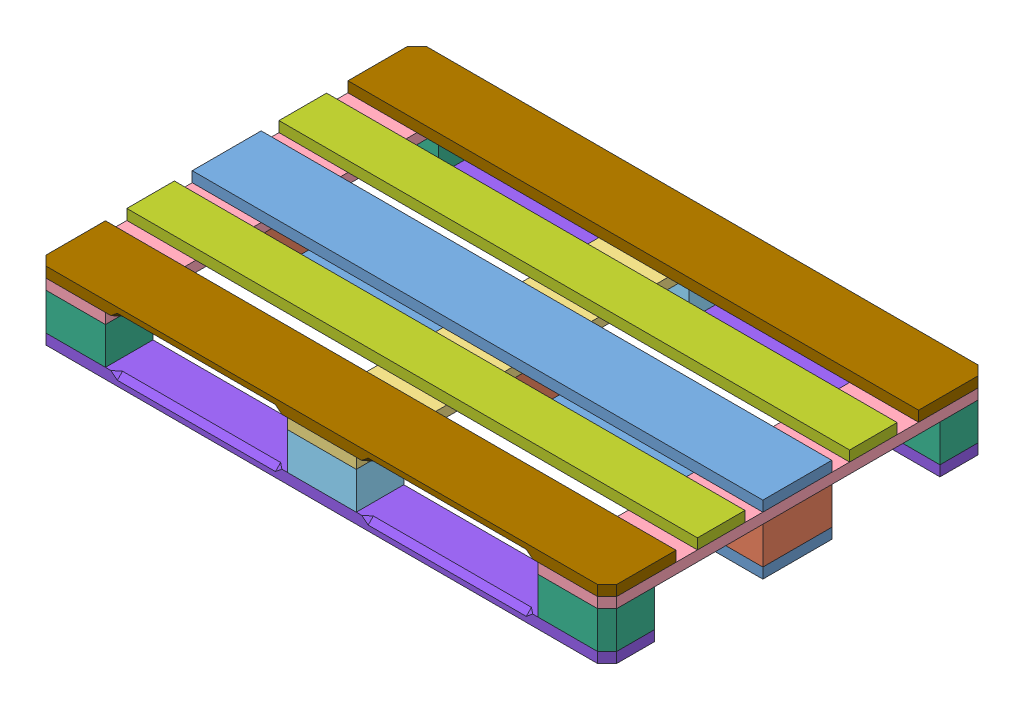
SolidWorks assembly PAL_EURO_120x80_EPAL, configuration Défaut. Lengths in mm.
Overall size (1200 144 800).
20 component instances, 9 part files, 62 mates.
Components (placement in the parent):
- brd-145x1200-1: brd-145x1200 [Default] x (-1 0 0) z (0 1 0) size (1200 145 22)
- blk-145x145-1: blk-145x145 [Default] at (0 22 0) x (-1 0 0) z (0 1 0) size (145 145 78)
- blk-145x145-2: blk-145x145 [Default] at (0 100 0) x (1 0 0) z (0 -1 0) size (145 145 78)
- blk-145x145-3: blk-145x145 [Default] at (0 100 527.5) x (0 0 -1) z (0 -1 0) size (145 145 78)
- brd-145x1200-2: brd-145x1200 [Default] at (0 144 0) x (1 0 0) z (0 -1 0) size (1200 145 22)
- trans-brd-cntr-145x800-1: trans-brd-cntr-145x800 [Default] at (0 122 0) x (0 0 1) z (0 -1 0) size (800 145 22)
- trans-brd-leader-145x800-1: trans-brd-leader-145x800 [Default] at (-600 122 0) x (0 0 1) z (0 -1 0) size (800 145 22)
- trans-brd-leader-145x800-2: trans-brd-leader-145x800 [Default] at (600 122 0) x (0 0 -1) z (0 -1 0) size (800 145 22)
- blk-100x145-1: blk-100x145 [Default] at (-527.5 22 -327.5) x (1 0 0) z (0 1 0) size (145 100 78)
- blk-100x145-2: blk-100x145 [Default] at (-527.5 100 327.5) x (1 0 0) z (0 -1 0) size (145 100 78)
- blk-100x145-corner-1: blk-100x145-corner [Default] at (455 22 -300) x (-1 0 0) z (0 1 0) size (145 100 78)
- blk-100x145-corner-2: blk-100x145-corner [Default] at (-455 22 300) x (1 0 0) z (0 1 0) size (145 100 78)
- blk-100x145-corner-3: blk-100x145-corner [Default] at (-455 100 -300) x (1 0 0) z (0 -1 0) size (145 100 78)
- blk-100x145-corner-4: blk-100x145-corner [Default] at (455 100 300) x (-1 0 0) z (0 -1 0) size (145 100 78)
- brd-100x1200-1: brd-100x1200 [Default] at (0 122 -160) x (1 0 0) z (0 1 0) size (1200 100 22)
- brd-100x1200-2: brd-100x1200 [Default] at (0 122 160) x (1 0 0) z (0 1 0) size (1200 100 22)
- leader deck brd bottom 100-1: leader deck brd bottom 100 [Défaut] at (0 0 350) x (0 0 -1) z (1 0 0) size (100 22 1200)
- leader deck brd bottom 100-2: leader deck brd bottom 100 [Défaut] at (0 0 -350) x (0 0 1) z (-1 0 0) size (100 22 1200)
- leader deck brd top 145-1: leader deck brd top 145 [Défaut] at (0 122 -327.5) x (0 0 1) z (-1 0 0) size (145 22 1200)
- leader deck brd top 145-2: leader deck brd top 145 [Défaut] at (0 122 327.5) x (0 0 -1) z (1 0 0) size (145 22 1200)
Mates (geometry in assembly coordinates):
- Coincident8: coincident: brd-145x1200-1, blk-145x145-1
- Coincident9: coincident: brd-145x1200-1, blk-145x145-1
- Coincident10: coincident: brd-145x1200-1, blk-145x145-1
- Coincident16: coincident: brd-145x1200-1, blk-145x145-2
- Coincident14: coincident: brd-145x1200-1, blk-145x145-2
- Coincident15: coincident: brd-145x1200-1, blk-145x145-2
- Coincident30: coincident: blk-145x145-1, trans-brd-leader-145x800-1
- Coincident31: coincident: blk-145x145-1, trans-brd-leader-145x800-1
- Coincident32: coincident: blk-145x145-1, trans-brd-leader-145x800-1
- Coincident33: coincident: blk-145x145-2, trans-brd-leader-145x800-2
- Coincident36: coincident: brd-145x1200-2, trans-brd-leader-145x800-2
- Coincident34: coincident: blk-145x145-2, trans-brd-leader-145x800-2
- Coincident35: coincident: blk-145x145-2, trans-brd-leader-145x800-2
- Coincident41: coincident: trans-brd-leader-145x800-2, blk-100x145-corner-4
- Coincident42: coincident: trans-brd-leader-145x800-2, blk-100x145-corner-4
- Coincident43: coincident: trans-brd-leader-145x800-2, blk-100x145-corner-4
- Coincident44: coincident: trans-brd-leader-145x800-1, blk-100x145-corner-3
- Coincident45: coincident: trans-brd-leader-145x800-1, blk-100x145-corner-3
- Coincident46: coincident: trans-brd-leader-145x800-1, blk-100x145-corner-3
- Coincident54: coincident: trans-brd-leader-145x800-2, blk-100x145-corner-1
- Coincident56: coincident: trans-brd-leader-145x800-2, blk-100x145-corner-1
- Coincident61: coincident: trans-brd-leader-145x800-1, blk-100x145-corner-2
- Coincident62: coincident: trans-brd-leader-145x800-1, blk-100x145-corner-2
- Coincident74: coincident: blk-100x145-corner-2, leader deck brd bottom 100-1
- Coincident75: coincident: blk-100x145-corner-4, leader deck brd bottom 100-1
- Coincident76: coincident: blk-100x145-corner-2, leader deck brd bottom 100-1
- Coincident78: coincident: blk-100x145-corner-3, leader deck brd bottom 100-2
- Coincident79: coincident: blk-100x145-corner-1, leader deck brd bottom 100-2
- Coincident80: coincident: blk-100x145-corner-3, leader deck brd bottom 100-2
- Coincident82: coincident: trans-brd-leader-145x800-2, leader deck brd top 145-1
- Coincident83: coincident: trans-brd-leader-145x800-2, leader deck brd top 145-1
- Coincident85: coincident: trans-brd-leader-145x800-1, brd-100x1200-1
- Distance4: distance: leader deck brd top 145-1, brd-100x1200-1
- Coincident86: coincident: trans-brd-leader-145x800-2, brd-100x1200-1
- Coincident87: coincident: trans-brd-leader-145x800-2, brd-100x1200-2
- Coincident88: coincident: trans-brd-leader-145x800-2, brd-100x1200-2
- Coincident89: coincident: trans-brd-leader-145x800-2, leader deck brd top 145-2
- Coincident90: coincident: trans-brd-leader-145x800-2, leader deck brd top 145-2
- Coincident91: coincident: trans-brd-leader-145x800-1, leader deck brd top 145-2
- Distance5: distance: brd-100x1200-2, leader deck brd top 145-2
- Coincident92: coincident: trans-brd-leader-145x800-1, brd-100x1200-2
- Coincident95: coincident: brd-145x1200-2, trans-brd-leader-145x800-1
- Coincident96: coincident: brd-145x1200-2, trans-brd-leader-145x800-1
- Coincident97: coincident: blk-145x145-1, brd-145x1200-2
- Coincident98: coincident: blk-145x145-1, brd-145x1200-2
- Coincident102: coincident: trans-brd-cntr-145x800-1, blk-100x145-1
- Coincident103: coincident: trans-brd-cntr-145x800-1, blk-100x145-1
- Coincident106: coincident: trans-brd-cntr-145x800-1, blk-100x145-1
- Coincident107: coincident: blk-100x145-2, leader deck brd bottom 100-1
- Coincident108: coincident: blk-100x145-2, leader deck brd bottom 100-1
- Coincident109: coincident: trans-brd-cntr-145x800-1, blk-100x145-2
- Coincident110: coincident: trans-brd-cntr-145x800-1, leader deck brd top 145-2
- Coincident111: coincident: blk-100x145-2, leader deck brd bottom 100-1
- Coincident112: coincident: blk-100x145-2, leader deck brd bottom 100-1
- Coincident113: coincident: trans-brd-cntr-145x800-1, blk-100x145-2
- Coincident115: coincident: trans-brd-cntr-145x800-1, blk-100x145-1
- Coincident116: coincident: trans-brd-cntr-145x800-1, blk-100x145-1
- Coincident134: coincident: brd-145x1200-1, blk-145x145-3
- Coincident136: coincident: blk-100x145-1, leader deck brd bottom 100-2
- Coincident137: coincident: blk-100x145-2, leader deck brd bottom 100-1
- Coincident138: coincident: blk-145x145-3, trans-brd-cntr-145x800-1
- Coincident139: coincident: brd-145x1200-1, blk-145x145-3
